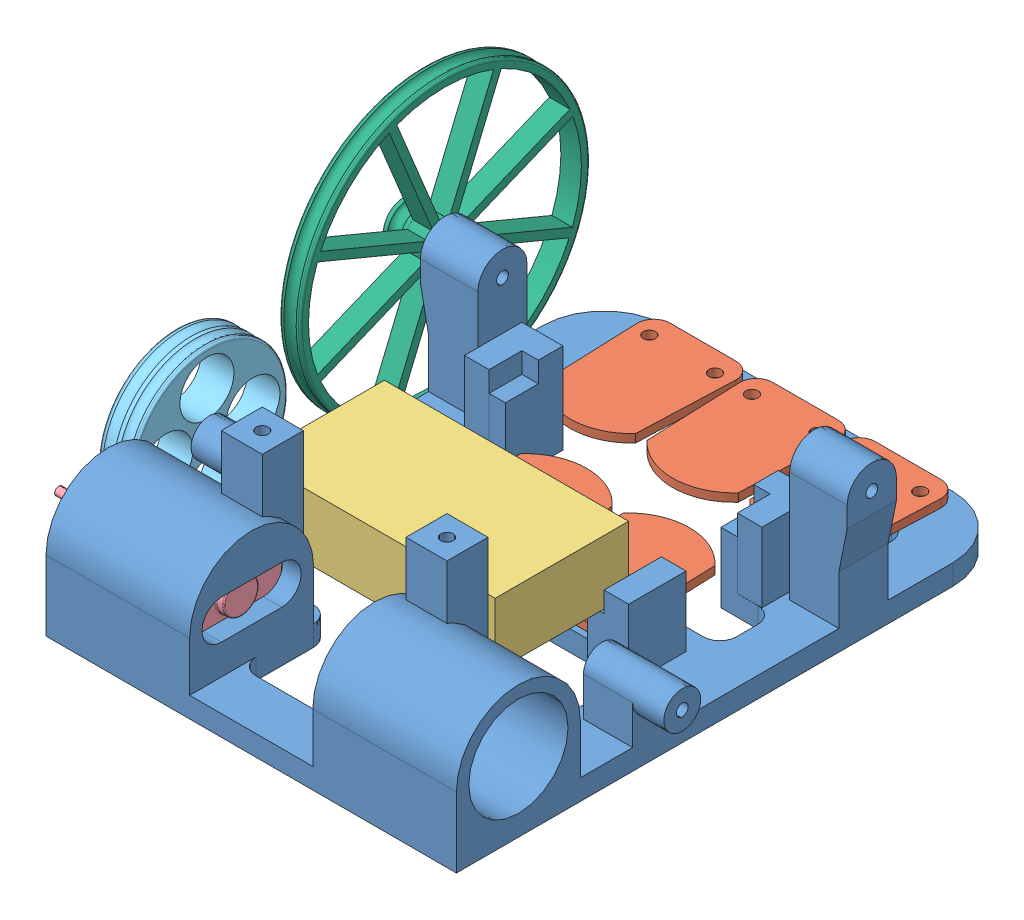
SolidWorks assembly Assem1, configuration Default. Lengths in mm.
Overall size (123.2 92.2 145.3).
11 component instances, 7 part files, 26 mates.
Components (placement in the parent):
- BODY6-1: BODY6 [Default] at origin size (115.2 44.5 136)
- SENSOR-1: SENSOR [Default] at (-25 5 -31.08) size (24 2 32.42)
- SENSOR-2: SENSOR [Default] at (25 5 -31.08) size (24 2 32.42)
- SENSOR-3: SENSOR [Default] at (12.5 5 34.15) x (-1 0 0) z (0 0 -1) size (24 2 32.42)
- SENSOR-4: SENSOR [Default] at (-12.5 5 34.15) x (-1 0 0) z (0 0 -1) size (24 2 32.42)
- SENSOR-5: SENSOR [Default] at (0 5 -31.08) size (24 2 32.42)
- BATTERY-1: BATTERY [Default] at (-0.5 17 53.55) x (0 0 1) z (-1 0 0) size (32.5 15.5 59.5)
- MM28Motor-1: MM28Motor [Default] at (-50 17.1 84.9) x (0 0.961516 0.274748) z (-1 0 0) size (24.2 24.2 44.5)
- WHEEL-1: WHEEL [Default] at (-65.6 14.5 52.57) x (0 0.058617 -0.998281) z (1 0 0) size (38 38 8)
- INTERMEDIATE65mm-1: INTERMEDIATE65mm [Default] at (-52 32 0.8) x (0 -0.922997 0.384807) z (-1 0 0) size (70.5 70.5 10)
- MOTOR_PULLEY-1: MOTOR_PULLEY [Default] at (-51.6 17.1 84.9) x (0 0 1) z (-1 0 0) size (10 10 5)
Mates (geometry in assembly coordinates):
- Coincident1: coincident anti-aligned: plane of BODY6-1 through (0 5 0) normal (0 1 0); plane of SENSOR-2 through (17 5 -31.08) normal (0 -1 0)
- Coincident2: coincident anti-aligned: plane of BODY6-1 through (0 5 0) normal (0 1 0); plane of SENSOR-4 through (-4.5 5 34.15) normal (0 -1 0)
- Coincident3: coincident anti-aligned: plane of BODY6-1 through (0 5 0) normal (0 1 0); plane of SENSOR-3 through (20.5 5 34.15) normal (0 -1 0)
- Coincident4: coincident anti-aligned: plane of BODY6-1 through (0 5 0) normal (0 1 0); plane of SENSOR-5 through (-8 5 -31.08) normal (0 -1 0)
- Coincident5: coincident anti-aligned: plane of BODY6-1 through (0 5 0) normal (0 1 0); plane of SENSOR-1 through (-33 5 -31.08) normal (0 -1 0)
- Concentric1: concentric anti-aligned: cylinder of BODY6-1 through (-20.5 -5 33.07) axis (0 1 0) radius 1.5; cylinder of SENSOR-4 through (-20.5 7 33.07) axis (0 -1 0) radius 1.5
- Concentric2: concentric anti-aligned: cylinder of BODY6-1 through (-4.5 -5 33.07) axis (0 1 0) radius 1.5; cylinder of SENSOR-4 through (-4.5 7 33.07) axis (0 -1 0) radius 1.5
- Concentric11: concentric anti-aligned: cylinder of BODY6-1 through (-33 -0.001 -30) axis (0 1 0) radius 1.5; cylinder of SENSOR-1 through (-33 7 -30) axis (0 -1 0) radius 1.5
- Concentric12: concentric anti-aligned: cylinder of BODY6-1 through (-17 -0.001 -30) axis (0 1 0) radius 1.5; cylinder of SENSOR-1 through (-17 7 -30) axis (0 -1 0) radius 1.5
- Concentric14: concentric anti-aligned: cylinder of BODY6-1 through (20.5 -5 33.07) axis (0 1 0) radius 1.5; cylinder of SENSOR-3 through (20.5 7 33.07) axis (0 -1 0) radius 1.5
- Concentric15: concentric anti-aligned: cylinder of BODY6-1 through (4.5 -5 33.07) axis (0 1 0) radius 1.5; cylinder of SENSOR-3 through (4.5 7 33.07) axis (0 -1 0) radius 1.5
- Concentric16: concentric anti-aligned: cylinder of SENSOR-5 through (8 7 -30) axis (0 -1 0) radius 1.5; cylinder of BODY6-1 through (8 -0.001 -30) axis (0 1 0) radius 1.5
- Coincident6: coincident aligned: cylinder of BODY6-1 through (-8 -0.001 -30) axis (0 1 0) radius 1.5; circle of SENSOR-5
- Concentric17: concentric anti-aligned: cylinder of BODY6-1 through (33 -0.001 -30) axis (0 1 0) radius 1.5; cylinder of SENSOR-2 through (33 7 -30) axis (0 -1 0) radius 1.5
- Concentric18: concentric anti-aligned: cylinder of BODY6-1 through (17 -0.001 -30) axis (0 1 0) radius 1.5; cylinder of SENSOR-2 through (17 7 -30) axis (0 -1 0) radius 1.5
- Coincident7: coincident anti-aligned: plane of BODY6-1 through (0 17 0) normal (0 1 0); plane of BATTERY-1 through (-0.5 17 53.55) normal (0 -1 0)
- Coincident8: coincident anti-aligned: plane of BODY6-1 through (50 32.2 69.8) normal (0 0 -1); plane of BATTERY-1 through (-30.25 32.5 69.8) normal (0 0 1)
- Coincident9: coincident anti-aligned: plane of BODY6-1 through (-30.25 22 0) normal (1 0 0); plane of BATTERY-1 through (-30.25 32.5 37.3) normal (-1 0 0)
- Concentric19: concentric aligned: cylinder of BODY6-1 through (-19.5 17.1 84.9) axis (-1 0 0) radius 12.1; cylinder of MM28Motor-1 through (-19.5 17.1 84.9) axis (-1 0 0) radius 12.1
- Coincident10: coincident anti-aligned: plane of BODY6-1 through (-19.5 0 0) normal (-1 0 0); plane of MM28Motor-1 through (-19.5 17.1 84.9) normal (1 0 0)
- Concentric20: concentric anti-aligned: cylinder of MM28Motor-1 through (-62 17.1 84.9) axis (1 0 0) radius 1; cylinder of MOTOR_PULLEY-1 through (-51.6 17.1 84.9) axis (-1 0 0) radius 1
- Coincident11: coincident anti-aligned: plane of MM28Motor-1 through (-51.6 17.1 84.9) normal (-1 0 0); plane of MOTOR_PULLEY-1 through (-51.6 17.1 84.9) normal (1 0 0)
- Concentric21: concentric anti-aligned: cylinder of BODY6-1 through (-39 14.5 52.57) axis (-1 0 0) radius 1.45; cylinder of WHEEL-1 through (-65.6 14.5 52.57) axis (1 0 0) radius 1.55
- Coincident12: coincident anti-aligned: plane of BODY6-1 through (-57.6 14.5 52.57) normal (-1 0 0); plane of WHEEL-1 through (-57.6 14.5 52.57) normal (1 0 0)
- Concentric22: concentric anti-aligned: cylinder of BODY6-1 through (-38 32 0.8) axis (-1 0 0) radius 1.45; cylinder of INTERMEDIATE65mm-1 through (-62 32 0.8) axis (1 0 0) radius 1.55
- Coincident13: coincident anti-aligned: plane of BODY6-1 through (-52 32 0.8) normal (-1 0 0); plane of INTERMEDIATE65mm-1 through (-52 45.5644 33.3357) normal (1 0 0)
